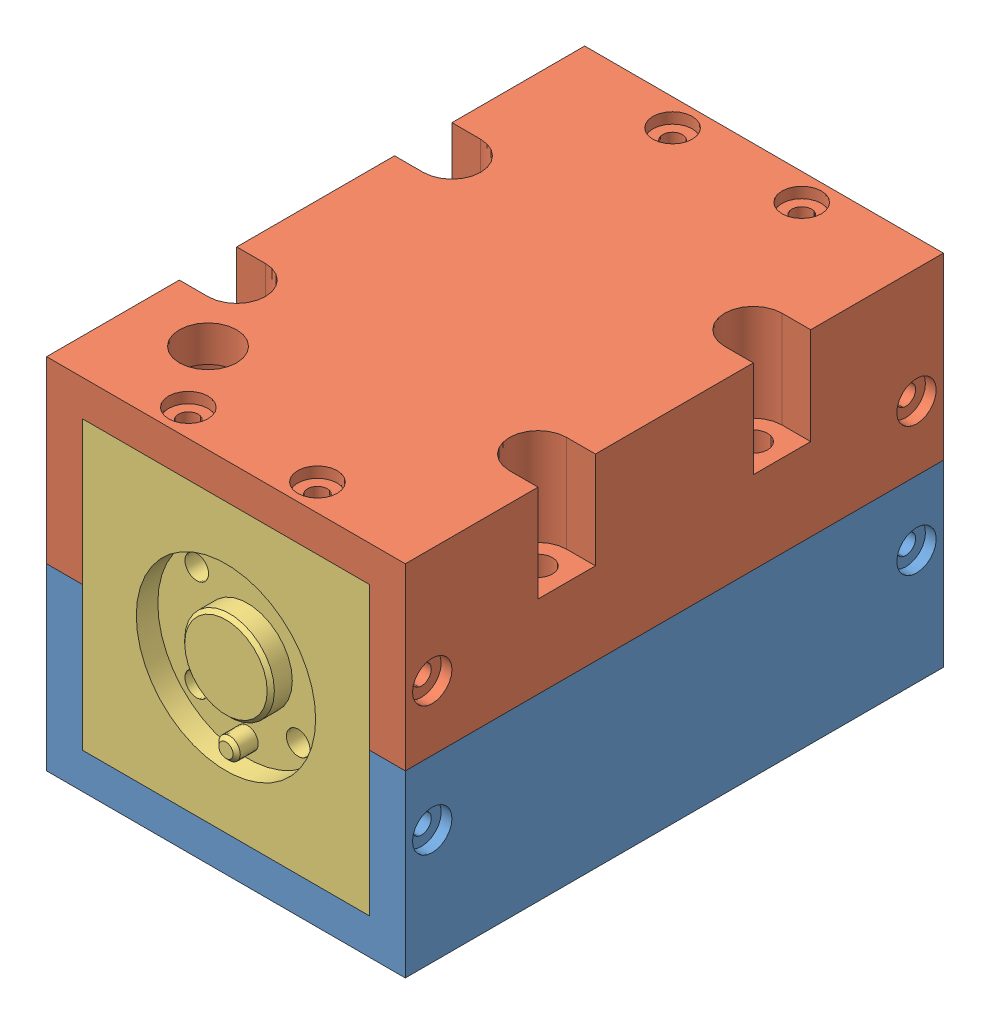
SolidWorks assembly Estrutura_1, configuration Default. Lengths in mm.
Overall size (100 100 226.33).
30 component instances, 8 part files, 47 mates.
Components (placement in the parent):
- Estrutura_bottom-1: Estrutura_bottom [Default] at (-19.0137 -38.1811 35.9729) size (100 50 150)
- Estrutura_top-1: Estrutura_top [Default] at (-19.0137 51.8189 35.9729) x (-1 0 0) z (0 0 1) size (100 50 150)
- Acoplamento_robot_50mm-1: Acoplamento_robot_50mm [Default] at (-19.0137 1.8189 20.9729) size (80 80 89.49)
- robot_fix-1: robot_fix [Default] at (-19.0137 1.8189 -99.0271) size (80 80 102.04)
- Acoplamento_garra_50mm-1: Acoplamento_garra_50mm [Default] at (-19.0137 1.8189 51.9729) size (60 60 102.04) (hidden)
- Socket Head Cap Screw_ISO-1: Socket Head Cap Screw_ISO [ISO 4762 M6 x 12 --- 12C] at (-33.1558 15.961 19.9729) x (0 0 1) z (0.069545 -0.997579 0) size (18 10 10) (hidden)
- Socket Head Cap Screw_ISO-2: Socket Head Cap Screw_ISO [ISO 4762 M6 x 12 --- 12C] at (-33.1558 -12.3233 19.9729) x (0 0 1) z (-0.998215 -0.059719 0) size (18 10 10) (hidden)
- Socket Head Cap Screw_ISO-3: Socket Head Cap Screw_ISO [ISO 4762 M6 x 12 --- 12C] at (-4.8715 15.961 19.9729) x (0 0 1) z (0.232824 -0.972519 0) size (18 10 10) (hidden)
- Socket Head Cap Screw_ISO-4: Socket Head Cap Screw_ISO [ISO 4762 M6 x 12 --- 12C] at (-4.8715 -12.3233 19.9729) x (0 0 1) z (0.16948 -0.985534 0) size (18 10 10) (hidden)
- Socket Head Cap Screw_ISO-5: Socket Head Cap Screw_ISO [ISO 4762 M8 x 40 --- 28C] at (22.9863 32.8189 -69.0271) x (0 -1 0) z (-0.159903 0 0.987133) size (48 13 13) (hidden)
- Socket Head Cap Screw_ISO-6: Socket Head Cap Screw_ISO [ISO 4762 M8 x 40 --- 28C] at (-61.0137 32.8189 -9.0271) x (0 -1 0) z (0.255557 0 0.966794) size (48 13 13) (hidden)
- Socket Head Cap Screw_ISO-7: Socket Head Cap Screw_ISO [ISO 4762 M8 x 40 --- 28C] at (-61.0137 32.8189 -69.0271) x (0 -1 0) z (0.293231 0 0.956042) size (48 13 13) (hidden)
- Socket Head Cap Screw_ISO-8: Socket Head Cap Screw_ISO [ISO 4762 M8 x 40 --- 28C] at (22.9863 32.8189 -9.0271) x (0 -1 0) z (0.1414 0 0.989953) size (48 13 13) (hidden)
- garra_teste-1: garra_teste [Default] at (-19.0137 1.8189 -133.0271) size (240 80 265.45) (hidden)
- Socket Button Head Screw_ISO-1: Socket Button Head Screw_ISO [ISO 7380 - M5 x 16 --- 16C] at (-65.7637 -16.1811 -106.5271) x (1 0 0) z (0 0.158363 0.987381) size (18.75 9.5 9.5) (hidden)
- Socket Button Head Screw_ISO-2: Socket Button Head Screw_ISO [ISO 7380 - M5 x 16 --- 16C] at (-1.0137 -45.9311 -106.5271) x (0 1 0) z (-0.205314 0 -0.978696) size (18.75 9.5 9.5) (hidden)
- Socket Button Head Screw_ISO-3: Socket Button Head Screw_ISO [ISO 7380 - M5 x 16 --- 16C] at (-1.0137 -45.9311 28.4729) x (0 1 0) z (0.856285 0 -0.516504) size (18.75 9.5 9.5) (hidden)
- Socket Button Head Screw_ISO-4: Socket Button Head Screw_ISO [ISO 7380 - M5 x 16 --- 16C] at (-68.7637 19.8189 28.4729) size (18.75 9.5 9.5) (hidden)
- Socket Button Head Screw_ISO-5: Socket Button Head Screw_ISO [ISO 7380 - M5 x 16 --- 16C] at (-68.7637 19.8189 -106.5271) size (18.75 9.5 9.5) (hidden)
- Socket Button Head Screw_ISO-6: Socket Button Head Screw_ISO [ISO 7380 - M5 x 16 --- 16C] at (-37.0137 -45.9311 -106.5271) x (0 1 0) z (0.831802 0 -0.555073) size (18.75 9.5 9.5) (hidden)
- Socket Button Head Screw_ISO-7: Socket Button Head Screw_ISO [ISO 7380 - M5 x 16 --- 16C] at (-37.0137 -45.9311 28.4729) x (0 1 0) z (0.5515 0 -0.834175) size (18.75 9.5 9.5) (hidden)
- Socket Button Head Screw_ISO-8: Socket Button Head Screw_ISO [ISO 7380 - M5 x 16 --- 16C] at (-68.7637 -16.1811 28.4729) size (18.75 9.5 9.5) (hidden)
- Socket Button Head Screw_ISO-9: Socket Button Head Screw_ISO [ISO 7380 - M5 x 16 --- 16C] at (-37.0137 51.5689 -106.5271) x (0 -1 0) z (-0.769255 0 -0.638941) size (18.75 9.5 9.5) (hidden)
- Socket Button Head Screw_ISO-10: Socket Button Head Screw_ISO [ISO 7380 - M5 x 16 --- 16C] at (-1.0137 51.5689 28.4729) x (0 -1 0) z (-0.994174 0 -0.107786) size (18.75 9.5 9.5) (hidden)
- Socket Button Head Screw_ISO-11: Socket Button Head Screw_ISO [ISO 7380 - M5 x 16 --- 16C] at (-1.0137 51.5689 -106.5271) x (0 -1 0) z (-0.707142 0 -0.707071) size (18.75 9.5 9.5) (hidden)
- Socket Button Head Screw_ISO-12: Socket Button Head Screw_ISO [ISO 7380 - M5 x 16 --- 16C] at (-37.0137 51.5689 28.4729) x (0 -1 0) z (-0.850405 0 -0.526129) size (18.75 9.5 9.5) (hidden)
- Socket Button Head Screw_ISO-13: Socket Button Head Screw_ISO [ISO 7380 - M5 x 16 --- 16C] at (30.7363 -16.1811 -106.5271) x (-1 0 0) z (0 0.738247 -0.67453) size (18.75 9.5 9.5) (hidden)
- Socket Button Head Screw_ISO-14: Socket Button Head Screw_ISO [ISO 7380 - M5 x 16 --- 16C] at (30.7363 -16.1811 28.4729) x (-1 0 0) z (0 0.699401 -0.71473) size (18.75 9.5 9.5) (hidden)
- Socket Button Head Screw_ISO-15: Socket Button Head Screw_ISO [ISO 7380 - M5 x 16 --- 16C] at (30.7363 19.8189 -106.5271) x (-1 0 0) z (0 0.656836 -0.754034) size (18.75 9.5 9.5) (hidden)
- Socket Button Head Screw_ISO-16: Socket Button Head Screw_ISO [ISO 7380 - M5 x 16 --- 16C] at (30.7363 19.8189 28.4729) x (-1 0 0) z (0 0.590405 -0.807107) size (18.75 9.5 9.5) (hidden)
Mates (geometry in assembly coordinates):
- Coincident22: coincident anti-aligned: plane of Estrutura_bottom-1 through (-69.0137 -38.1811 -114.0271) normal (0 1 0); plane of Acoplamento_robot_50mm-1 through (-59.0137 -38.1811 35.9729) normal (0 -1 0)
- Coincident23: coincident anti-aligned: plane of Estrutura_bottom-1 through (20.9863 1.8189 -114.0271) normal (-1 0 0); plane of Acoplamento_robot_50mm-1 through (20.9863 41.8189 35.9729) normal (1 0 0)
- Coincident24: coincident aligned: plane of Estrutura_bottom-1 through (-69.0137 -48.1811 35.9729) normal (0 0 1); plane of Acoplamento_robot_50mm-1 through (-59.0137 -38.1811 35.9729) normal (0 0 1)
- Coincident26: coincident anti-aligned: plane of Estrutura_bottom-1 through (-69.0137 -38.1811 -114.0271) normal (0 1 0); plane of robot_fix-1 through (-59.0137 -38.1811 -114.0271) normal (0 -1 0)
- Coincident27: coincident anti-aligned: plane of Estrutura_bottom-1 through (20.9863 1.8189 -114.0271) normal (-1 0 0); plane of robot_fix-1 through (20.9863 41.8189 -114.0271) normal (1 0 0)
- Coincident28: coincident aligned: plane of Estrutura_bottom-1 through (-69.0137 -48.1811 -114.0271) normal (0 0 -1); plane of robot_fix-1 through (-59.0137 -38.1811 -114.0271) normal (0 0 -1)
- Concentric153: concentric aligned: cylinder of Estrutura_bottom-1 through (22.9863 1.8189 -9.0271) axis (0 1 0) radius 3.4; cylinder of Estrutura_top-1 through (22.9863 24.8189 -9.0271) axis (0 1 0) radius 4
- Concentric154: concentric aligned: cylinder of Estrutura_bottom-1 through (-61.0137 1.8189 -69.0271) axis (0 1 0) radius 3.4; cylinder of Estrutura_top-1 through (-61.0137 24.8189 -69.0271) axis (0 1 0) radius 4
- Coincident29: coincident anti-aligned: plane of Estrutura_bottom-1 through (20.9863 1.8189 35.9729) normal (0 1 0); plane of Estrutura_top-1 through (20.9863 1.8189 -114.0271) normal (0 -1 0)
- Concentric155: concentric aligned: cylinder of Estrutura_top-1 through (-61.0137 24.8189 -9.0271) axis (0 1 0) radius 4; cylinder of Socket Head Cap Screw_ISO-6 through (-61.0137 64.5689 -9.0271) axis (0 1 0) radius 4
- Coincident30: coincident anti-aligned: plane of Estrutura_top-1 through (-61.0137 24.8189 -9.0271) normal (0 1 0); plane of Socket Head Cap Screw_ISO-6 through (-54.7295 24.8189 -10.6882) normal (0 -1 0)
- Concentric156: concentric aligned: cylinder of Estrutura_top-1 through (22.9863 24.8189 -9.0271) axis (0 1 0) radius 4; cylinder of Socket Head Cap Screw_ISO-8 through (22.9863 64.5689 -9.0271) axis (0 1 0) radius 4
- Coincident31: coincident anti-aligned: plane of Estrutura_top-1 through (22.9863 24.8189 -9.0271) normal (0 1 0); plane of Socket Head Cap Screw_ISO-8 through (29.421 24.8189 -9.9462) normal (0 -1 0)
- Concentric157: concentric aligned: cylinder of Estrutura_top-1 through (22.9863 24.8189 -69.0271) axis (0 1 0) radius 4; cylinder of Socket Head Cap Screw_ISO-5 through (22.9863 64.5689 -69.0271) axis (0 1 0) radius 4
- Coincident33: coincident anti-aligned: plane of Estrutura_top-1 through (22.9863 24.8189 -69.0271) normal (0 1 0); plane of Socket Head Cap Screw_ISO-5 through (29.4027 24.8189 -67.9877) normal (0 -1 0)
- Concentric158: concentric aligned: cylinder of Estrutura_top-1 through (-61.0137 24.8189 -69.0271) axis (0 1 0) radius 4; cylinder of Socket Head Cap Screw_ISO-7 through (-61.0137 64.5689 -69.0271) axis (0 1 0) radius 4
- Coincident35: coincident anti-aligned: plane of Estrutura_top-1 through (-61.0137 24.8189 -69.0271) normal (0 1 0); plane of Socket Head Cap Screw_ISO-7 through (-54.7994 24.8189 -70.9331) normal (0 -1 0)
- Concentric159: concentric aligned: cylinder of robot_fix-1 through (-59.0137 19.8189 -106.5271) axis (-1 0 0) radius 2.1; cylinder of Socket Button Head Screw_ISO-5 through (-68.7637 19.8189 -106.5271) axis (-1 0 0) radius 2.5
- Coincident36: coincident anti-aligned: plane of Estrutura_top-1 through (-66.0137 17.0689 -106.5271) normal (-1 0 0); plane of Socket Button Head Screw_ISO-5 through (-66.0137 22.3189 -106.5271) normal (1 0 0)
- Concentric160: concentric aligned: cylinder of Acoplamento_robot_50mm-1 through (-59.0137 19.8189 28.4729) axis (-1 0 0) radius 2.1; cylinder of Socket Button Head Screw_ISO-4 through (-68.7637 19.8189 28.4729) axis (-1 0 0) radius 2.5
- Coincident37: coincident anti-aligned: plane of Estrutura_top-1 through (-66.0137 17.0689 28.4729) normal (-1 0 0); plane of Socket Button Head Screw_ISO-4 through (-66.0137 22.3189 28.4729) normal (1 0 0)
- Concentric161: concentric aligned: cylinder of Acoplamento_robot_50mm-1 through (-59.0137 -16.1811 28.4729) axis (-1 0 0) radius 2.1; cylinder of Socket Button Head Screw_ISO-8 through (-68.7637 -16.1811 28.4729) axis (-1 0 0) radius 2.5
- Coincident38: coincident anti-aligned: plane of Estrutura_bottom-1 through (-66.0137 -13.4311 28.4729) normal (-1 0 0); plane of Socket Button Head Screw_ISO-8 through (-66.0137 -13.6811 28.4729) normal (1 0 0)
- Concentric162: concentric aligned: cylinder of robot_fix-1 through (-1.0137 41.8189 -106.5271) axis (0 1 0) radius 2.1; cylinder of Socket Button Head Screw_ISO-11 through (-1.0137 51.5689 -106.5271) axis (0 1 0) radius 2.5
- Concentric163: concentric aligned: cylinder of robot_fix-1 through (-37.0137 41.8189 -106.5271) axis (0 1 0) radius 2.1; cylinder of Socket Button Head Screw_ISO-9 through (-37.0137 51.5689 -106.5271) axis (0 1 0) radius 2.5
- Concentric164: concentric aligned: cylinder of Acoplamento_robot_50mm-1 through (-1.0137 41.8189 28.4729) axis (0 1 0) radius 2.1; cylinder of Socket Button Head Screw_ISO-10 through (-1.0137 51.5689 28.4729) axis (0 1 0) radius 2.5
- Concentric165: concentric aligned: cylinder of Acoplamento_robot_50mm-1 through (-37.0137 41.8189 28.4729) axis (0 1 0) radius 2.1; cylinder of Socket Button Head Screw_ISO-12 through (-37.0137 51.5689 28.4729) axis (0 1 0) radius 2.5
- Concentric166: concentric aligned: cylinder of robot_fix-1 through (20.9863 -16.1811 -106.5271) axis (1 0 0) radius 2.1; cylinder of Socket Button Head Screw_ISO-13 through (30.7363 -16.1811 -106.5271) axis (1 0 0) radius 2.5
- Concentric167: concentric aligned: cylinder of Acoplamento_robot_50mm-1 through (20.9863 -16.1811 28.4729) axis (1 0 0) radius 2.1; cylinder of Socket Button Head Screw_ISO-14 through (30.7363 -16.1811 28.4729) axis (1 0 0) radius 2.5
- Concentric168: concentric aligned: cylinder of robot_fix-1 through (20.9863 19.8189 -106.5271) axis (1 0 0) radius 2.1; cylinder of Socket Button Head Screw_ISO-15 through (30.7363 19.8189 -106.5271) axis (1 0 0) radius 2.5
- Concentric169: concentric aligned: cylinder of Acoplamento_robot_50mm-1 through (20.9863 19.8189 28.4729) axis (1 0 0) radius 2.1; cylinder of Socket Button Head Screw_ISO-16 through (30.7363 19.8189 28.4729) axis (1 0 0) radius 2.5
- Concentric170: concentric aligned: cylinder of robot_fix-1 through (-1.0137 -38.1811 -106.5271) axis (0 -1 0) radius 2.1; cylinder of Socket Button Head Screw_ISO-2 through (-1.0137 -45.9311 -106.5271) axis (0 -1 0) radius 2.5
- Concentric171: concentric aligned: cylinder of robot_fix-1 through (-37.0137 -38.1811 -106.5271) axis (0 -1 0) radius 2.1; cylinder of Socket Button Head Screw_ISO-6 through (-37.0137 -45.9311 -106.5271) axis (0 -1 0) radius 2.5
- Concentric172: concentric aligned: cylinder of Acoplamento_robot_50mm-1 through (-1.0137 -38.1811 28.4729) axis (0 -1 0) radius 2.1; cylinder of Socket Button Head Screw_ISO-3 through (-1.0137 -45.9311 28.4729) axis (0 -1 0) radius 2.5
- Concentric173: concentric aligned: cylinder of Acoplamento_robot_50mm-1 through (-37.0137 -38.1811 28.4729) axis (0 -1 0) radius 2.1; cylinder of Socket Button Head Screw_ISO-7 through (-37.0137 -45.9311 28.4729) axis (0 -1 0) radius 2.5
- Coincident39: coincident anti-aligned: plane of Estrutura_top-1 through (-3.7637 48.8189 28.4729) normal (0 1 0); plane of Socket Button Head Screw_ISO-10 through (-1.2831 48.8189 30.9584) normal (0 -1 0)
- Coincident40: coincident anti-aligned: plane of Estrutura_top-1 through (-39.7637 48.8189 28.4729) normal (0 1 0); plane of Socket Button Head Screw_ISO-12 through (-38.329 48.8189 30.599) normal (0 -1 0)
- Coincident41: coincident anti-aligned: plane of Estrutura_top-1 through (-3.7637 48.8189 -106.5271) normal (0 1 0); plane of Socket Button Head Screw_ISO-11 through (-2.7813 48.8189 -104.7592) normal (0 -1 0)
- Coincident42: coincident anti-aligned: plane of Estrutura_top-1 through (-39.7637 48.8189 -106.5271) normal (0 1 0); plane of Socket Button Head Screw_ISO-9 through (-38.611 48.8189 -104.6039) normal (0 -1 0)
- Coincident43: coincident anti-aligned: plane of Estrutura_top-1 through (27.9863 17.0689 -106.5271) normal (1 0 0); plane of Socket Button Head Screw_ISO-15 through (27.9863 21.704 -104.885) normal (-1 0 0)
- Coincident44: coincident anti-aligned: plane of Estrutura_bottom-1 through (27.9863 -13.4311 -106.5271) normal (1 0 0); plane of Socket Button Head Screw_ISO-13 through (27.9863 -14.4948 -104.6814) normal (-1 0 0)
- Coincident45: coincident anti-aligned: plane of Estrutura_bottom-1 through (27.9863 -13.4311 28.4729) normal (1 0 0); plane of Socket Button Head Screw_ISO-14 through (27.9863 -14.3943 30.2214) normal (-1 0 0)
- Coincident46: coincident anti-aligned: plane of Estrutura_top-1 through (27.9863 17.0689 28.4729) normal (1 0 0); plane of Socket Button Head Screw_ISO-16 through (27.9863 21.8367 29.949) normal (-1 0 0)
- Coincident47: coincident anti-aligned: plane of Estrutura_bottom-1 through (1.7363 -43.1811 -106.5271) normal (0 -1 0); plane of Socket Button Head Screw_ISO-2 through (1.4331 -43.1811 -107.0403) normal (0 1 0)
- Coincident48: coincident anti-aligned: plane of Estrutura_bottom-1 through (-34.2637 -43.1811 -106.5271) normal (0 -1 0); plane of Socket Button Head Screw_ISO-6 through (-35.626 -43.1811 -104.4476) normal (0 1 0)
- Coincident49: coincident anti-aligned: plane of Estrutura_bottom-1 through (1.7363 -43.1811 28.4729) normal (0 -1 0); plane of Socket Button Head Screw_ISO-3 through (0.2776 -43.1811 30.6137) normal (0 1 0)
- Coincident50: coincident anti-aligned: plane of Estrutura_bottom-1 through (-34.2637 -43.1811 28.4729) normal (0 -1 0); plane of Socket Button Head Screw_ISO-7 through (-34.9282 -43.1811 29.8517) normal (0 1 0)
